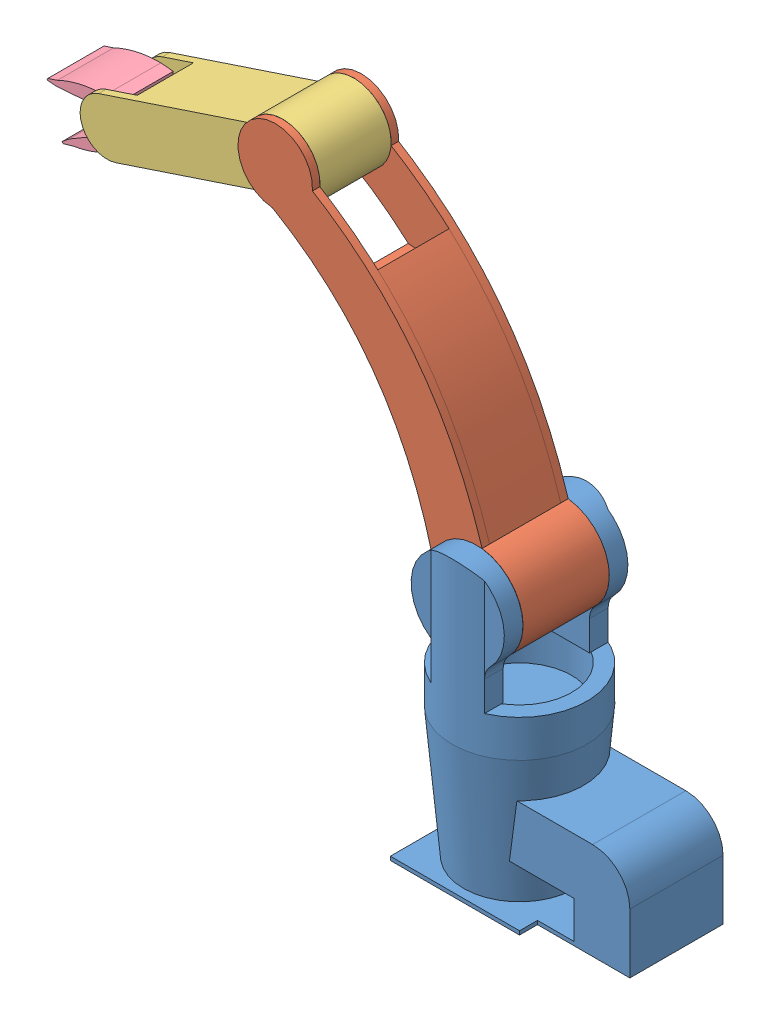
SolidWorks assembly 2 DOF ROBO ARM, configuration Default. Lengths in mm.
Overall size (322.63 320.86 72.25).
5 component instances, 4 part files, 6 mates.
Components (placement in the parent):
- ARM base-1: ARM base [Default] at (8.7441 25.6226 186.5508) size (120.29 158.12 72.25)
- ARM 1-1: ARM 1 [Default] at (8.7441 158.7403 163.4045) x (0.845875 0.533381 0) z (0 0 1) size (65.09 226.75 46.2)
- ARM 2-1: ARM 2 [Default] at (-99.2779 305.4816 167.4045) x (0.948982 0.315331 0) z (0 0 1) size (133.71 40 38.15)
- GRAPPLING ARM-1: GRAPPLING ARM [Default] at (-191.1331 267.3173 171.4245) x (-0.7703 -0.637681 0) z (0 0 1) size (36.87 10.91 30.13)
- GRAPPLING ARM-2: GRAPPLING ARM [Default] at (-195.707 281.0823 201.5545) x (-0.996472 0.083931 0) z (0 0 -1) size (36.87 10.91 30.13)
Mates (geometry in assembly coordinates):
- Hinge1: hinge anti-aligned: cylinder of ARM base-1 through (8.7441 158.7403 161.4045) axis (0 0 1) radius 5; cylinder of ARM 1-1 through (8.7441 158.7403 160.4045) axis (0 0 1) radius 5.02; plane of ARM 1-1 through (8.7441 158.7403 163.4045) normal (0 0 -1); plane of ARM base-1 through (8.7441 187.6226 163.4045) normal (0 0 1)
- Hinge4: hinge anti-aligned: cylinder of ARM 1-1 through (27.0632 340.0307 165.2045) axis (0 0 1) radius 5; cylinder of ARM 2-1 through (27.0632 340.0307 218.4795) axis (0 0 -1) radius 5.05; plane of ARM 2-1 through (27.0632 340.0307 167.4045) normal (0 0 -1); plane of ARM 1-1 through (8.7441 158.7403 167.4045) normal (0 0 1)
- Concentric2: concentric aligned: cylinder of ARM 2-1 through (91.4412 415.8552 203.5545) axis (0 0 -1) radius 2.5; cylinder of GRAPPLING ARM-1 through (91.4412 415.8552 201.5545) axis (0 0 -1) radius 2.51
- Coincident2: coincident anti-aligned: plane of ARM 2-1 through (27.0632 340.0307 201.5545) normal (0 0 -1); plane of GRAPPLING ARM-1 through (91.4412 415.8552 201.5545) normal (0 0 1)
- Concentric3: concentric anti-aligned: cylinder of ARM 2-1 through (-195.707 281.0823 203.5545) axis (0 0 -1) radius 2.5; cylinder of GRAPPLING ARM-2 through (-195.707 281.0823 171.4245) axis (0 0 1) radius 2.51
- Coincident3: coincident anti-aligned: plane of ARM 2-1 through (-99.2779 305.4816 201.5545) normal (0 0 -1); plane of GRAPPLING ARM-2 through (-195.707 281.0823 201.5545) normal (0 0 1)
